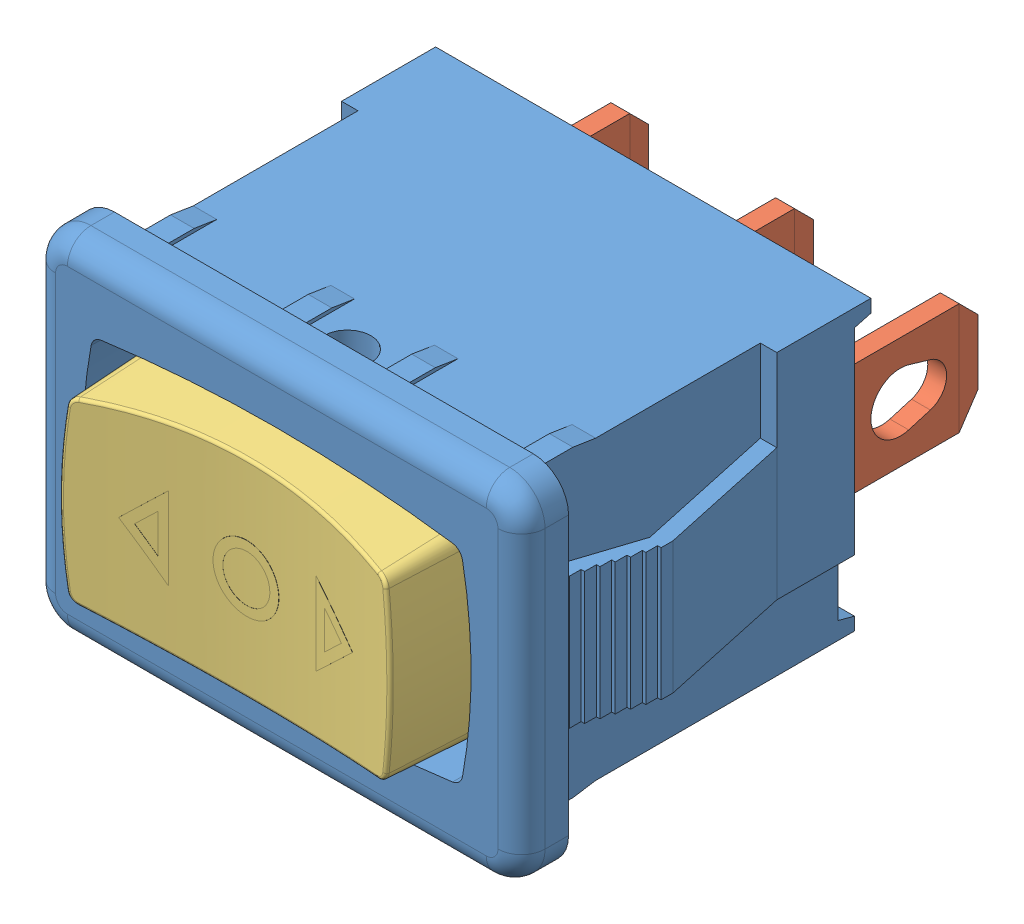
SolidWorks assembly R1966IBLKBLKHF, configuration Default. Lengths in mm.
Overall size (20.94 14.8 24.82).
5 component instances, 3 part files, 0 mates.
Components (placement in the parent):
- Copy of R1966 HOUSING STD^R1966IBLKBLKHF-1: Copy of R1966 HOUSING STD^R1966IBLKBLKHF [Default] at origin size (20.94 14.8 16) (virtual)
- Copy of R1966 TERM F^R1966IBLKBLKHF-1: Copy of R1966 TERM F^R1966IBLKBLKHF [Default] at (-7 0 0.7) size (0.8 6.88 8.3) (virtual)
- Copy of R1966 TERM F^R1966IBLKBLKHF-2: Copy of R1966 TERM F^R1966IBLKBLKHF [Default] at (0 0 0.7) size (0.8 6.88 8.3) (virtual)
- Copy of R1966 TERM F^R1966IBLKBLKHF-3: Copy of R1966 TERM F^R1966IBLKBLKHF [Default] at (7 0 0.7) size (0.8 6.88 8.3) (virtual)
- Copy of ACUATOR H^R1966IBLKBLKHF-1: Copy of ACUATOR H^R1966IBLKBLKHF [Default] at (0 0 11.47) x (-1 0 0) z (0 0 1) size (14.75 11.6 8.75) (virtual)
